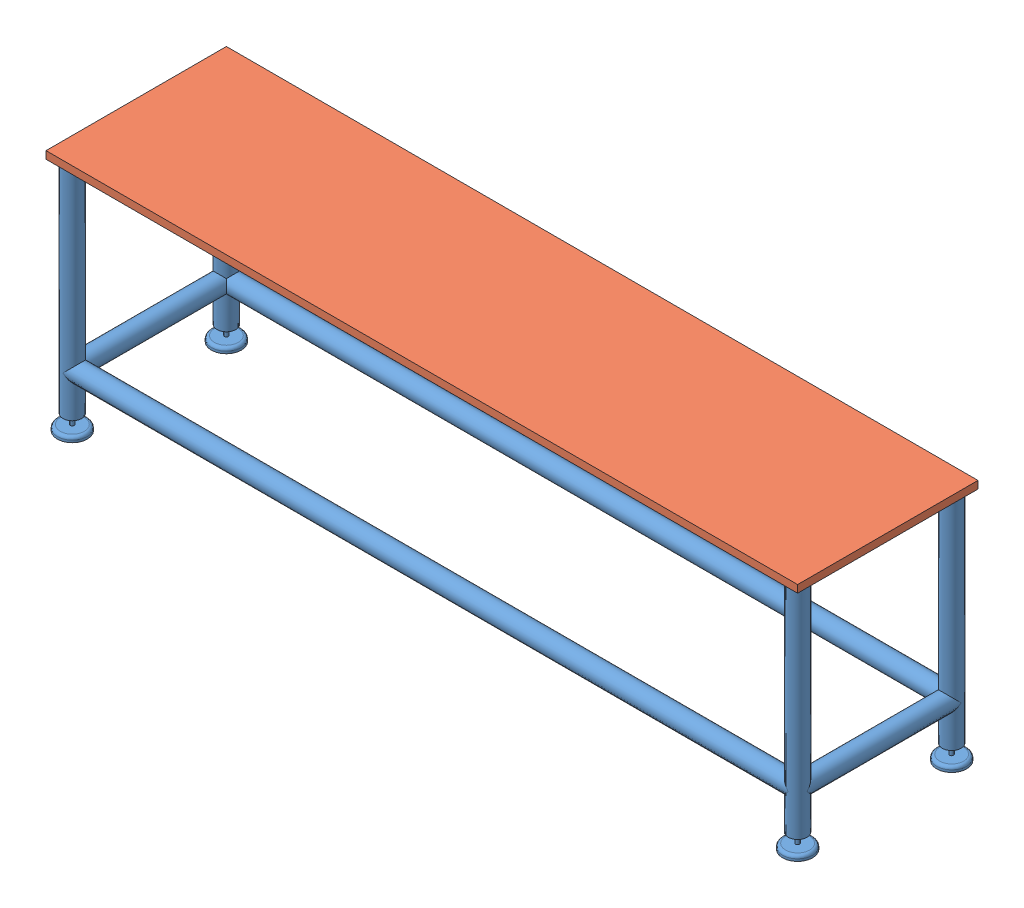
SolidWorks assembly Assem1, configuration Default. Lengths in mm.
Overall size (1276.35 409.58 311.15).
2 component instances, 2 part files, 3 mates.
Components (placement in the parent):
- frame-1: frame [Default] at (460.452 525.6122 1011.3011) size (1276.35 396.88 311.15)
- steel plate-1: steel plate [Default] at (430.6021 830.4122 1385.2244) size (1270 12.7 304.8)
Mates (geometry in assembly coordinates):
- Coincident1: coincident: plane of frame-1 through (-152.323 830.4122 1141.4761) normal (0 1 0); plane of steel plate-1 through (430.6021 830.4122 1385.2244) normal (0 -1 0)
- Width1: width: plane of steel plate-1 through (-174.548 843.1122 858.9011) normal (-1 0 0); plane of steel plate-1 through (1095.452 843.1122 858.9011) normal (1 0 0); plane of frame-1 through (1089.102 824.0622 1011.3011) normal (1 0 0); plane of frame-1 through (-168.198 824.0622 1011.3011) normal (-1 0 0)
- Width2: width anti-aligned: plane of steel plate-1 through (-174.548 843.1122 858.9011) normal (0 0 -1); plane of steel plate-1 through (-174.548 843.1122 1163.7011) normal (0 0 1); plane of frame-1 through (460.452 824.0622 1157.3511) normal (0 0 1); plane of frame-1 through (460.452 824.0622 865.2511) normal (0 0 -1)
